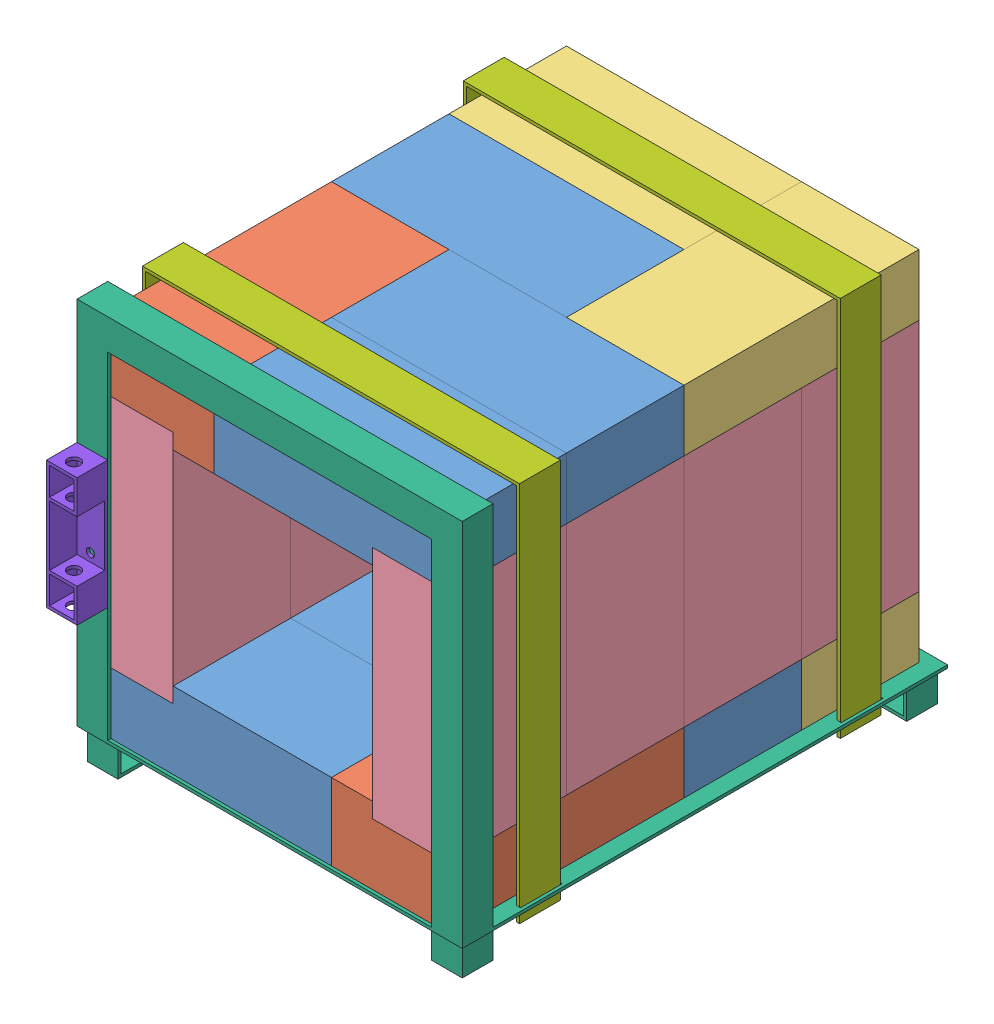
SolidWorks assembly Final Assembly, configuration Default. Lengths in mm.
Overall size (377 392 505).
32 component instances, 8 part files, 10 mates.
Components (placement in the parent):
- Long-1: Long [Default] at origin size (353.06 350 465.32)
  - Heat Treat Asm Top-Bot Alt Long-1: Heat Treat Asm Top-Bot Alt Long [Default] at (93.1186 153.6522 453.2582) size (345 75 460)
    - Brick-Sharp-BackCut-1: Brick-Sharp-BackCut [Default] at (102.0414 124.8114 164.7515) size (230 75 115)
    - Brick-Sharp-SideCut-1: Brick-Sharp-SideCut [Default] at (274.5414 124.8114 107.2515) x (0 0 1) z (-1 0 0) size (230 75 115)
    - Brick-Sharp-BackCut-2: Brick-Sharp-BackCut [Default] at (102.0414 124.8114 49.7515) size (230 75 115)
    - Brick-Sharp-BackCut-3: Brick-Sharp-BackCut [Default] at (217.0414 124.8114 -65.2485) x (-1 0 0) z (0 0 -1) size (230 75 115)
    - Brick-Sharp-BackLeftCut-2: Brick-Sharp-BackLeftCut [Default] at (217.0414 124.8114 -180.2485) x (-1 0 0) z (0 0 -1) size (230 75 115)
    - Brick-Sharp-BackLeftCut-3: Brick-Sharp-BackLeftCut [Default] at (44.5414 124.8114 -122.7485) x (0 0 1) z (-1 0 0) size (230 75 115)
  - Heat Treat Asm Top-Bot Alt Long-2: Heat Treat Asm Top-Bot Alt Long [Default] at (412.2014 678.275 453.2582) x (-1 0 0) z (0 0 1) size (345 75 460)
    - Brick-Sharp-BackCut-1: Brick-Sharp-BackCut [Default] at (102.0414 124.8114 164.7515) size (230 75 115)
    - Brick-Sharp-SideCut-1: Brick-Sharp-SideCut [Default] at (274.5414 124.8114 107.2515) x (0 0 1) z (-1 0 0) size (230 75 115)
    - Brick-Sharp-BackCut-2: Brick-Sharp-BackCut [Default] at (102.0414 124.8114 49.7515) size (230 75 115)
    - Brick-Sharp-BackCut-3: Brick-Sharp-BackCut [Default] at (217.0414 124.8114 -65.2485) x (-1 0 0) z (0 0 -1) size (230 75 115)
    - Brick-Sharp-BackLeftCut-2: Brick-Sharp-BackLeftCut [Default] at (217.0414 124.8114 -180.2485) x (-1 0 0) z (0 0 -1) size (230 75 115)
    - Brick-Sharp-BackLeftCut-3: Brick-Sharp-BackLeftCut [Default] at (44.5414 124.8114 -122.7485) x (0 0 1) z (-1 0 0) size (230 75 115)
  - Heat Treat Asm Back-1: Heat Treat Asm Back [Default] at (559.1645 290.8305 184.2616) x (-0.008726 0.008727 0.999924) z (-0.999962 0 -0.008727) size (462.63 234.01 79.01)
    - Brick-Sharp-1: Brick-Sharp [Default] at (91.3299 124.3408 170.7235) x (-0.008727 -0.999962 0) z (-0.999924 0.008726 0.008727) size (230 75 115)
    - Brick-Sharp-2: Brick-Sharp [Default] at (206.3211 123.3373 169.7199) x (0.008727 0.999962 0) z (-0.999924 0.008726 0.008727) size (230 75 115)
    - Brick-Sharp-3: Brick-Sharp [Default] at (436.3036 121.3303 167.7128) x (-0.008727 -0.999962 0) z (0.999924 -0.008726 -0.008727) size (230 75 115)
    - Brick-Sharp-4: Brick-Sharp [Default] at (321.3124 122.3338 168.7164) x (-0.008727 -0.999962 0) z (0.999924 -0.008726 -0.008727) size (230 75 115)
  - Heat Treat Asm Back-2: Heat Treat Asm Back [Default] at (-53.8445 290.8305 706.7578) x (0.008726 0.008727 -0.999924) z (0.999962 0 0.008727) size (462.63 234.01 79.01)
    - Brick-Sharp-1: Brick-Sharp [Default] at (91.3299 124.3408 170.7235) x (-0.008727 -0.999962 0) z (-0.999924 0.008726 0.008727) size (230 75 115)
    - Brick-Sharp-2: Brick-Sharp [Default] at (206.3211 123.3373 169.7199) x (0.008727 0.999962 0) z (-0.999924 0.008726 0.008727) size (230 75 115)
    - Brick-Sharp-3: Brick-Sharp [Default] at (436.3036 121.3303 167.7128) x (-0.008727 -0.999962 0) z (0.999924 -0.008726 -0.008727) size (230 75 115)
    - Brick-Sharp-4: Brick-Sharp [Default] at (321.3124 122.3338 168.7164) x (-0.008727 -0.999962 0) z (0.999924 -0.008726 -0.008727) size (230 75 115)
  - Heat Treat Asm Back Alt-1: Heat Treat Asm Back Alt [Default] at (386.4278 496.0717 124.4337) x (0 -1 0) z (-1 0 0) size (230 75 195)
    - Brick-Sharp-1: Brick-Sharp [Default] at (80.1081 128.5759 173.7678) size (230 75 115)
    - Brick-Sharp-Trimmed-1: Brick-Sharp-Trimmed [Default] at (80.1081 128.5759 58.7678) size (230 75 80)
- Base-Frame-1: Base-Frame [Default] at (252.66 239.4636 441.0097) size (377 392 475)
- TensionFrame-1: TensionFrame [Default] at (252.66 413.4238 598.5097) size (369 373 40)
- TensionFrame-2: TensionFrame [Default] at (252.66 413.4238 284.5097) size (369 373 40)
- Hinge-1: Hinge [Default] at (79.16 415.9636 693.5097) x (0 0 1) z (1 0 0) size (30 125 30)
Mates (geometry in assembly coordinates):
- Coincident1: coincident anti-aligned: plane of Long-1/Heat Treat Asm Top-Bot Alt Long-1/Brick-Sharp-BackCut-1 through (195.16 240.9636 618.0097) normal (0 -1 0); plane of Base-Frame-1 through (252.66 240.9636 441.0097) normal (0 1 0)
- Distance1: distance = 3 mm aligned: plane of Base-Frame-1 through (64.16 240.9636 678.5097) normal (0 0 1); plane of Long-1/Heat Treat Asm Top-Bot Alt Long-1/Brick-Sharp-BackCut-1 through (80.16 315.9636 675.5097) normal (0 0 1)
- Distance2: distance = 16 mm aligned: plane of Base-Frame-1 through (64.16 240.9636 203.5097) normal (-1 0 0); plane of Long-1/Heat Treat Asm Top-Bot Alt Long-1/Brick-Sharp-BackCut-1 through (80.16 315.9636 560.5097) normal (-1 0 0)
- Coincident5: coincident anti-aligned: plane of Base-Frame-1 through (434.16 237.9636 618.5097) normal (1 0 0); plane of TensionFrame-1 through (434.16 226.9238 618.5097) normal (-1 0 0)
- Coincident6: coincident anti-aligned: plane of Base-Frame-1 through (434.16 237.9636 618.5097) normal (0 0 -1); plane of TensionFrame-1 through (252.66 413.4238 618.5097) normal (0 0 1)
- Coincident7: coincident anti-aligned: plane of Base-Frame-1 through (434.16 237.9636 304.5097) normal (0 0 -1); plane of TensionFrame-2 through (252.66 413.4238 304.5097) normal (0 0 1)
- Coincident10: coincident aligned: line of TensionFrame-1 through (437.16 226.9238 618.5097) axis (0 0 -1); line of TensionFrame-2 through (437.16 226.9238 304.5097) axis (0 0 -1)
- Coincident11: coincident: plane of Base-Frame-1 through (64.16 240.9636 678.5097) normal (0 0 1); plane of Hinge-1 through (-7.1759 415.9636 678.5097) normal (0 0 -1)
- Distance3: distance = 112.5 mm: plane of Hinge-1 through (94.16 353.4636 681.5097) normal (0 -1 0); plane of Base-Frame-1 through (252.66 240.9636 441.0097) normal (0 1 0)
- Coincident13: coincident aligned: plane of Base-Frame-1 through (64.16 240.9636 203.5097) normal (-1 0 0); plane of Hinge-1 through (64.16 353.4636 681.5097) normal (-1 0 0)
